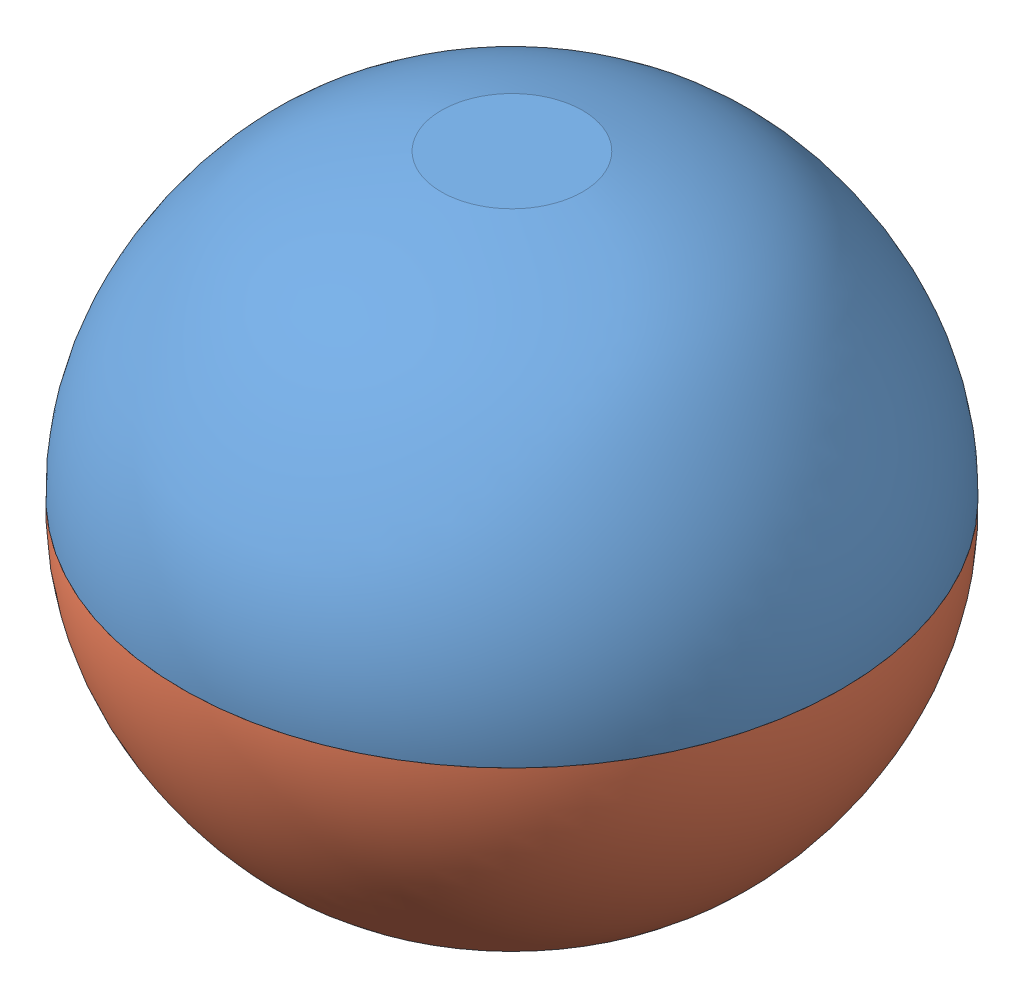
SolidWorks assembly Baugr1, configuration Standard. Lengths in mm.
Overall size (281.7 253.85 281.7).
4 component instances, 4 part files, 6 mates.
Components (placement in the parent):
- BLANDA_BLANK_IKEA_28cm-1: BLANDA_BLANK_IKEA_28cm [Standard] at (0 1096.0806 377.7127) size (281.7 128 281.7)
- BLANDA_BLANK_IKEA_28cm_mit_Loch_OK-1: BLANDA_BLANK_IKEA_28cm_mit_Loch_OK [Standard] at (0 1096.0806 377.7127) x (0 0 1) z (1 0 0) size (281.7 180.85 281.7)
- Teil1^Baugr1-2: Teil1^Baugr1 [Standard] at origin (virtual)
- Teil2^Baugr1-1: Teil2^Baugr1 [Standard] at (0 1157.0806 377.7127) x (0 0 1) z (0 -1 0) size (160 40 20) (virtual)
Mates (geometry in assembly coordinates):
- Deckungsgleich1: coincident anti-aligned: circle of BLANDA_BLANK_IKEA_28cm-1; circle of BLANDA_BLANK_IKEA_28cm_mit_Loch-1
- Deckungsgleich2: coincident aligned: plane of BLANDA_BLANK_IKEA_28cm_mit_Loch_OK-1 through (0 1096.0806 377.7127) normal (1 0 0)
- Deckungsgleich3: coincident anti-aligned: plane of BLANDA_BLANK_IKEA_28cm_mit_Loch_OK-1 through (0 1147.0806 317.7127) normal (0 1 0); plane of Teil2^Baugr1-1 through (0 1147.0806 377.7127) normal (0 -1 0)
- Deckungsgleich4: coincident anti-aligned: plane of BLANDA_BLANK_IKEA_28cm_mit_Loch_OK-1 through (-20 1096.0806 317.7127) normal (1 0 0); plane of Teil2^Baugr1-1 through (-20 1147.0806 457.7127) normal (-1 0 0)
- Konzentrisch1: concentric aligned: cylinder of BLANDA_BLANK_IKEA_28cm_mit_Loch_OK-1 through (0 1137.0806 312.7127) axis (0 1 0) radius 2.75; cylinder of Teil2^Baugr1-1 through (0 1147.0806 312.7127) axis (0 1 0) radius 2.75
- Konzentrisch2: concentric aligned: cylinder of BLANDA_BLANK_IKEA_28cm_mit_Loch_OK-1 through (0 1137.0806 442.7127) axis (0 1 0) radius 2.75; cylinder of Teil2^Baugr1-1 through (0 1147.0806 442.7127) axis (0 1 0) radius 2.75
